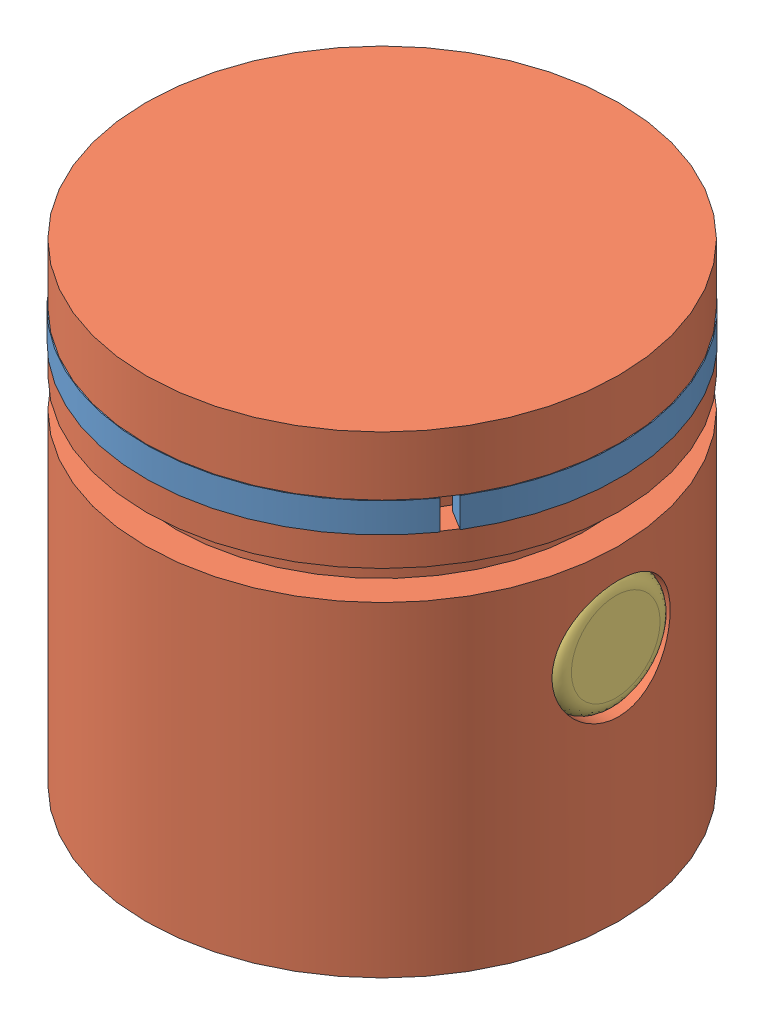
SolidWorks assembly dhirendra task 4, configuration Default. Lengths in mm.
Overall size (44.15 32 44.15).
3 component instances, 3 part files, 5 mates.
Components (placement in the parent):
- 3 p c 20-2: 3 p c 20 [Default] at (0 26 -16) x (-0.52298 0 0.852345) z (-0.852345 0 -0.52298) size (32.1 2 32.1)
- 3 p c 19-2: 3 p c 19 [Default] at origin size (32 32 32)
- 3 p c 21-2: 3 p c 21 [Default] at (-15.1906 16 -16) x (0 -0.958402 0.285423) z (0 0.285423 0.958402) size (8 31 8)
Mates (geometry in assembly coordinates):
- Coincident1: coordinate: point of 3 p c 19-2
- Concentric1: concentric anti-aligned: cylinder of 3 p c 20-2 through (0 28 -16) axis (0 -1 0) radius 14.5; cylinder of 3 p c 19-2 through (0 32 -16) axis (0 1 0) radius 14
- Concentric2: concentric anti-aligned: cylinder of 3 p c 20-2 through (0 28 -16) axis (0 -1 0) radius 14.5; cylinder of 3 p c 19-2 through (0 32 -16) axis (0 1 0) radius 14
- Coincident3: coincident anti-aligned: plane of 3 p c 20-2 through (0 28 -16) normal (0 1 0); plane of 3 p c 19-2 through (0 28 0) normal (0 -1 0)
- Concentric4: concentric anti-aligned: cylinder of 3 p c 19-2 through (-16 16 -16) axis (1 0 0) radius 4; cylinder of 3 p c 21-2 through (15.8094 16 -16) axis (-1 0 0) radius 4
